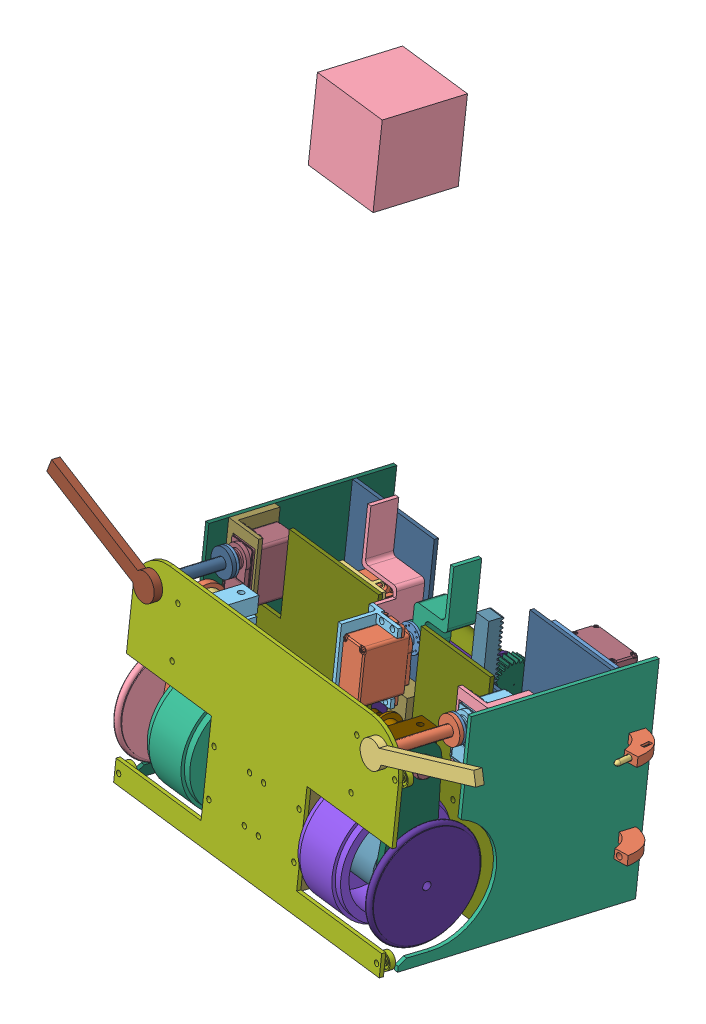
SolidWorks assembly assemblage, configuration Default. Lengths in mm.
Overall size (483.19 497.28 376.15).
92 component instances, 58 part files, 7 mates.
Components (placement in the parent):
- Assem2^assemblage-1: Assem2^assemblage [Default] at origin size (100.3 104.34 84.15)
  - Access_HS-645_BrasRondPetitModele-1: Access_HS-645_BrasRondPetitModele [Défaut] at (-370.7751 -387.697 -20.5572) x (0.014805 -0.999149 0.038511) z (-0.138062 0.036103 0.989765) size (20 5 20)
  - 3-1: 3 [По умолчанию] at (-408.8734 -398.3893 -24.6127) x (0.002879 -0.992343 0.123476) z (-0.138823 0.121884 0.982788) size (53 41.52 20)
  - support statuette-1: support statuette [Default] at (-391.2391 -403.7974 -8.2234) x (-0.002879 0.992343 -0.123476) z (0.138823 -0.121884 -0.982788) size (54 40.5 24)
  - 4-1: 4 [Default] at (-394.7864 -367.7937 -36.5924) x (-0.990313 -0.019971 -0.13741) z (-0.138823 0.121884 0.982788) size (40.67 72.69 34)
  - 3-2: 3 [По умолчанию] at (-353.2671 -390.1635 36.15) x (0.002879 -0.992343 0.123476) z (0.990313 0.019971 0.13741) size (53 41.52 20)
  - 6-1: 6 [Default] at (-364.4184 -365.3949 40.1426) x (0.002879 -0.992343 0.123476) z (0.138823 -0.121884 -0.982788) size (53 30.58 30.75)
  - 2'-1: 2' [Default] at (-347.3265 -385.4811 -7.3447) x (-0.990313 -0.019971 -0.13741) z (0.138823 -0.121884 -0.982788) size (40.4 72.21 20)
  - Access_HS-645_BrasRondPetitModele-2: Access_HS-645_BrasRondPetitModele [Défaut] at (-347.9512 -384.9326 -2.9221) x (0.831423 0.553492 0.048799) z (-0.538018 0.823887 -0.178175) size (20 5 20)
- assemblage v1.1-1: assemblage v1.1 [Default] at (-362.4566 -430.5503 30.4693) x (0.990313 0.019971 0.13741) z (-0.138823 0.121884 0.982788) size (426.3 229.5 291.49)
  - Assem2-1: Assem2 [Default] at (-85.1208 -142.9391 -147.0358) size (284.49 174.6 174.6)
    - BASE-1: BASE [Default] at (61.0944 135.0485 201.8855) size (250 158.15 3)
    - ASSEMB TAMB+SUPPORT-1: ASSEMB TAMB+SUPPORT [Default] at (133.4152 89.0177 175.4805) x (-1 0 0) z (0 0.999702 -0.024415) size (106.04 84.84 84.84)
      - Tombour-1: Tombour [Défaut] at (-5.9119 -3.3103 11.7008) size (103.56 84.84 84.84)
      - small_roue-1: small_roue [Défaut] at (29.0381 -3.3103 11.7008) x (0 0.151035 0.988528) z (-1 0 0) size (23.1 23.1 19.4)
      - support_roulement-1: support_roulement [Défaut] at (9.0881 -3.3103 11.7008) x (0 -0.024415 -0.999702) z (1 0 0) size (45 40 8)
      - accouplement moteur-1: accouplement moteur [Défaut] at (-2.9119 -3.3103 11.7008) x (1 0 0) z (0 -0.034188 0.999415) size (9 25 25)
      - support_roulement-2: support_roulement [Défaut] at (42.4881 -3.3103 11.7008) x (0 -0.024415 -0.999702) z (1 0 0) size (45 40 8)
    - kala-1: kala [Défaut] at (37.3271 135.6343 191.8855) size (90 70 10)
    - assem_enco-7: assem_enco [Default] at (-278.6181 -106.4767 -4.9991) x (0.135936 0.843541 0.519577) z (0.008939 -0.525468 0.850766) size (130.48 81.47 114.09) (flexible)
      - hex screw gradeab fine_iso-1: hex screw gradeab fine_iso [ISO 8676 - M8x1.0 x 16-N] at (389.3011 -418.9502 9.0475) x (-0.135936 0.990677 -0.008939) z (0.955436 0.133476 0.2633) size (21.3 15.01 13)
      - Encodeur TR-1: Encodeur TR [Défaut] at (324.9983 -380.9981 47.0052) x (-0.884066 -0.125369 -0.450234) z (0.135936 -0.990677 0.008939) size (37.8 37.8 52.6)
      - levier-1: levier [Default] at (329.8376 -416.2662 47.3234) x (-0.829282 -0.108844 0.548127) z (0.135936 -0.990677 0.008939) size (114.35 58.34 5)
      - axe-2: axe [Default] at (388.5807 -413.6996 9.0001) x (0.135936 -0.990677 0.008939) z (-0.521438 -0.079215 -0.849604) size (50 24 24)
      - Roue Encodeur-2: Roue Encodeur [Défaut] at (332.9737 -439.1212 47.5296) x (-0.135936 0.990677 -0.008939) z (-0.830604 -0.109044 0.546083) size (16.57 81 81)
      - Part1-2: Part1 [Default] at (363.5392 -389.8747 -1.4264) x (-0.843541 -0.111005 0.525468) z (0.135936 -0.990677 0.008939) size (50 50 15)
    - Mirrorassem_enco-8: Mirrorassem_enco [Default] at (439.2724 -106.4767 -4.9991) x (-0.135936 0.843541 0.519577) z (0.008939 0.525468 -0.850766) size (148.4 84.96 134.9) (flexible)
      - hex screw gradeab fine_iso-1: hex screw gradeab fine_iso [ISO 8676 - M8x1.0 x 16-N] at (389.3011 -418.9502 -9.0475) x (-0.135936 0.990677 0.008939) z (-0.955436 -0.133476 0.2633) size (21.3 15.01 13)
      - MirrorEncodeur TR-1: MirrorEncodeur TR [Défaut] at (324.9983 -380.9981 -47.0052) x (-0.884066 -0.125369 0.450234) z (-0.135936 0.990677 0.008939) size (37.8 37.8 52.6)
      - Mirrorlevier-1: Mirrorlevier [Default] at (329.8376 -416.2662 -47.3234) x (-0.829282 -0.108844 -0.548127) z (-0.135936 0.990677 0.008939) size (114.35 58.34 5)
      - Mirroraxe-1: Mirroraxe [Default] at (388.5807 -413.6996 -9.0001) x (0.135936 -0.990677 -0.008939) z (0.521438 0.079215 -0.849604) size (50 24 24)
      - MirrorRoue Encodeur-1: MirrorRoue Encodeur [Défaut] at (332.9737 -439.1212 -47.5296) x (-0.135936 0.990677 0.008939) z (0.830604 0.109044 0.546083) size (16.57 81 81)
      - MirrorPart1-1: MirrorPart1 [Default] at (363.5392 -389.8747 1.4264) x (-0.843541 -0.111005 -0.525468) z (-0.135936 0.990677 0.008939) size (50 50 15)
    - MirrorASSEMB TAMB+SUPPORT-4: MirrorASSEMB TAMB+SUPPORT [Default] at (27.239 89.0177 175.4805) x (1 0 0) z (0 -0.999702 0.024415) size (88.4 84.84 84.84)
      - MirrorTombour-1: MirrorTombour [Défaut] at (-5.9119 -3.3103 -11.7008) size (40 84.84 84.84)
      - Mirrorsmall_roue-1: Mirrorsmall_roue [Défaut] at (29.0381 -3.3103 -11.7008) x (0 0.151035 -0.988528) z (1 0 0) size (23.1 23.1 19.4)
      - Mirrorsupport_roulement-1: Mirrorsupport_roulement [Défaut] at (9.0881 -3.3103 -11.7008) x (0 -0.024415 0.999702) z (-1 0 0) size (45 40 8)
      - Mirroraccouplement moteur-1: Mirroraccouplement moteur [Défaut] at (-2.9119 -3.3103 -11.7008) x (1 0 0) z (0 0.034188 0.999415) size (9 25 25)
      - Mirrorsupport_roulement-2: Mirrorsupport_roulement [Défaut] at (42.4881 -3.3103 -11.7008) x (0 -0.024415 0.999702) z (-1 0 0) size (45 40 8)
  - assemblage servo-1: assemblage servo [Default] at (-160.2326 88.9637 31.5129) x (0.690395 -0.305055 -0.655969) z (-0.682474 0.02613 -0.730443) size (163.61 67.11 94.82)
    - Access_HS-645_BrasRondPetitModele-1: Access_HS-645_BrasRondPetitModele [Défaut] at (65.5627 21.9831 -12.3813) x (0.698273 0.5203 -0.491633) z (-0.286565 0.832544 0.474079) size (20 5 20)
    - axe support-1: axe support [Default] at (62.6109 22.8388 -15.6683) x (0.748633 0.040573 -0.661742) z (-0.655969 0.190152 -0.730443) size (20 20 53)
    - dezzzez-1: dezzzez [Default] at (23.9087 34.0577 -58.7644) x (0.75207 0.082615 -0.653885) z (0.655969 -0.190152 0.730443) size (108.66 20 6)
    - support el servo-1: support el servo [Default] at (72.965 19.2307 -6.0551) x (0.690395 -0.239966 -0.682474) z (-0.655969 0.190152 -0.730443) size (28.16 56.8 33)
    - Servo-D-2: Servo-D [По умолчанию] at (94.1961 24.0869 15.8447) x (0.305055 0.951976 -0.02613) z (-0.690395 0.239966 0.682474) size (53 41.52 20)
  - r4-12-4-2: r4-12-4 [Default] at (-113.1077 46.2048 55.8497) x (-0.657011 -0.753881 0) z (0.753881 -0.657011 0) size (12 4 12)
  - 7it limin-1: 7it limin [Default] at (-126.7937 5.619 -27.8276) x (0 0 1) z (-1 0 0) size (170.25 158.15 3)
  - assemblage moteur+etage-1: assemblage moteur+etage [Default] at (-103.1195 95.8777 149.8599) x (1 0 0) z (0 0 -1) size (244 158.15 47.87)
    - ETAGE MOUTEUR-1: ETAGE MOUTEUR [Default] at (256.6337 145.964 177.6302) size (244 158.15 3)
    - moteur +roue-1: moteur +roue [Default] at (27.1868 130.6075 195.5653) x (1 0 0) z (0 -1 0) size (86.85 44.87 38.33)
      - moteur+support-1: moteur+support [Default] at (-21.5557 -32.4755 -56.3756) size (79.5 40.9 38.33)
        - supportMoteur-1: supportMoteur [Default] at (46.2429 19.2403 29.8006) size (51 40.7 38)
        - moteurKacem-1: moteurKacem [Default] at (22.5429 39.3442 49.0318) x (-1 0 0) z (0 0.033028 0.999454) size (79.5 37 37)
      - small_roue-1: small_roue [Défaut] at (47.089 13.8648 -7.575) x (0 0.568944 0.822376) z (-1 0 0) size (23.1 23.1 19.4)
    - moteur +roue-2: moteur +roue [Default] at (169.7129 145.7575 195.5653) x (-1 0 0) z (0 1 0) size (86.85 44.87 38.33)
      - moteur+support-1: moteur+support [Default] at (-21.5557 -32.4755 -56.3756) size (79.5 40.9 38.33)
        - supportMoteur-1: supportMoteur [Default] at (46.2429 19.2403 29.8006) size (51 40.7 38)
        - moteurKacem-1: moteurKacem [Default] at (22.5429 39.3442 49.0318) x (-1 0 0) z (0 0.033028 0.999454) size (79.5 37 37)
      - small_roue-1: small_roue [Défaut] at (47.089 13.8648 -7.575) x (0 0.568944 0.822376) z (-1 0 0) size (23.1 23.1 19.4)
  - Mirrorassemblage servo-2: Mirrorassemblage servo [Default] at (150.6452 88.9637 31.5129) x (-0.690395 -0.305055 -0.655969) z (-0.682474 -0.02613 0.730443) size (163.61 67.11 94.82)
    - MirrorAccess_HS-645_BrasRondPetitModele-1: MirrorAccess_HS-645_BrasRondPetitModele [Défaut] at (65.5627 21.9831 12.3813) x (0.698273 0.5203 0.491633) z (0.286565 -0.832544 0.474079) size (20 5 20)
    - Mirroraxe support-1: Mirroraxe support [Default] at (62.6109 22.8388 15.6683) x (0.748633 0.040573 0.661742) z (0.655969 -0.190152 -0.730443) size (20 20 53)
    - Mirrordezzzez-1: Mirrordezzzez [Default] at (23.9087 34.0577 58.7644) x (0.75207 0.082615 0.653885) z (-0.655969 0.190152 0.730443) size (108.66 20 6)
    - Mirrorsupport el servo-1: Mirrorsupport el servo [Default] at (72.965 19.2307 6.0551) x (0.690395 -0.239966 0.682474) z (0.655969 -0.190152 -0.730443) size (28.16 56.8 33)
    - MirrorServo-D-1: MirrorServo-D [По умолчанию] at (94.1961 24.0869 -15.8447) x (0.305055 0.951976 0.02613) z (0.690395 -0.239966 0.682474) size (53 41.52 20)
  - Mirror7it limin-2: Mirror7it limin [Default] at (117.2063 5.619 -27.8276) x (0 0 1) z (-1 0 0) size (170.25 167.82 3)
  - Mirrorr4-12-4-3: Mirrorr4-12-4 [Default] at (103.5203 46.2048 55.8497) x (0.657011 -0.753881 0) z (0.753881 0.657011 0) size (12 4 12)
  - replique-1: replique [Default] at (-4.7937 -88.5236 -90.7703) size (60 60 60)
  - cale replique-1: cale replique [Default] at (-6.1208 -58.5236 -25.7703) x (0 0 -1) z (0 1 0) size (5 30 3)
  - Assem-1: Assem [Default] at (-2.3071 5.8511 16.0473) size (244 158.15 86.12) (flexible)
    - MirrorAccess_HS-645_BrasRondPetitModele-1: MirrorAccess_HS-645_BrasRondPetitModele [Défaut] at (-52.4866 -77.6747 -107.8176) x (-0.658163 0 0.752875) z (0.752875 0 0.658163) size (20 5 20)
    - Servo-D-1: Servo-D [По умолчанию] at (-52.4866 -38.6747 -117.8176) x (0 0 -1) z (-1 0 0) size (53 41.52 20)
    - s9af-1: s9af [Default] at (-2.4866 26.161 -112.8176) size (244 158.15 3)
    - tched replique-1: tched replique [Default] at (-52.4866 -87.1747 -107.8176) x (-0.813575 0 -0.58146) z (0 1 0) size (49.05 41.23 25)
    - support et servo-1: support et servo [Default] at (-73.3835 -34.6287 -140.8176) size (41 29.15 56.5)
  - attach servo-1: attach servo [Default] at (28.2063 -60.4931 -53.0632) x (0 1 0) z (-1 0 0) size (33.78 63 3)
  - Assem6-2: Assem6 [Default] at (-10.3274 -15.7264 -107.2975) x (0 -1 0) z (1 0 0) size (96 86.77 81.2)
    - rack spur rectangular_am-1: rack spur rectangular_am [Metric - Rack-spur - rectangular 1M 20PA 12FW 10PH 100L---SAll] at (-60.2027 -10.5273 12) size (96 51 24)
    - spur gear_am-1: spur gear_am [2] at (-3.4027 14.3327 0) x (0 0 1) z (-0.856307 0.516467 0) size (10 31.88 32)
    - moteur-1: moteur [Default] at (-3.4027 14.3327 -7) x (-0.862944 -0.5053 0) z (0 0 -1) size (24 24 68.2)
    - support moteur-1: support moteur [Default] at (-3.1173 -5.1673 -4) x (0 0 1) z (-1 0 0) size (32.8 32.7 26.4)
  - Mirrorr4-12-4-5: Mirrorr4-12-4 [Default] at (117.8895 -86.0211 50.8497) x (0.657011 -0.753881 0) z (0.753881 0.657011 0) size (12 4 12)
  - Mirrorr4-12-4-6: Mirrorr4-12-4 [Default] at (116.9176 34.3236 50.8497) x (0.171062 -0.98526 0) z (0.98526 0.171062 0) size (12 4 12)
  - Mirrorr4-12-4-7: Mirrorr4-12-4 [Default] at (-126.131 34.2944 50.8497) x (0.015905 -0.999874 0) z (0.999874 0.015905 0) size (12 4 12)
  - Mirrorr4-12-4-8: Mirrorr4-12-4 [Default] at (-124.7919 -85.9696 50.8497) x (0.685449 -0.728121 0) z (0.728121 0.685449 0) size (12 4 12)
  - Assem8-3: Assem8 [Default] at (123.6422 -106.1666 -217.2827) x (0.80126 0.594877 -0.06406) z (-0.112906 0.255477 0.9602) size (95.61 147.83 66.82)
    - Servo-D-1: Servo-D [По умолчанию] at (67.1215 121.1491 150.7487) x (-0.80126 0.587567 0.112906) z (-0.06406 -0.271869 0.9602) size (53 41.52 20)
    - MirrorAccess_HS-645_BrasRondPetitModele_-1: MirrorAccess_HS-645_BrasRondPetitModele_ [Défaut] at (52.2313 85.9312 139.7838) x (0.287559 0.095019 -0.953038) z (-0.75062 0.640405 -0.162634) size (20 5 20)
    - Part7-1: Part7 [Default] at (66.588 102.8456 155.9452) x (-0.80126 0.587567 0.112906) z (-0.06406 -0.271869 0.9602) size (60.3 37.24 23)
    - fouille_bras-2: fouille_bras [Default] at (49.5544 82.5016 138.6342) x (-0.752668 0.639706 -0.15578) z (-0.594877 -0.762137 -0.255477) size (56.89 34.39 72)
    - porte_fil-2: porte_fil [Default] at (77.1126 49.4264 154.9436) x (-0.070641 0.366169 -0.927863) z (-0.684204 0.659091 0.312192) size (28 4 4)
- 1-2: 1 [Default] at (-435.3748 -79.9916 -79.545) x (0.990313 0.019971 0.13741) z (0.002879 -0.992343 0.123476) size (61 61 61)
Mates (geometry in assembly coordinates):
- Distance3: distance = 6 mm: plane of 1-2 through (-409.2287 -136.1979 -37.8469) normal (-0.138823 0.121884 0.982788); plane of assemblage v1.1-1/assemblage moteur+etage-1/ETAGE MOUTEUR-1 through (-206.0136 -480.9378 27.5074) normal (0.138823 -0.121884 -0.982788)
- Parallel1: parallel: plane of assemblage v1.1-1/7it limin-1 through (-493.9044 -472.4602 39.3317) normal (-0.990313 -0.019971 -0.13741); plane of 1-2 through (-461.1696 -144.8511 -106.1789) normal (-0.990313 -0.019971 -0.13741)
- Coincident24: coincident: plane of Assem2^assemblage-1/3-1 through (-371.7654 -387.717 -20.6946) normal (0.990313 0.019971 0.13741); plane of assemblage v1.1-1/assemblage moteur+etage-1/ETAGE MOUTEUR-1 through (-374.0356 -368.897 -7.0691) normal (0.990313 0.019971 0.13741)
- Coincident25: coincident: plane of Assem2^assemblage-1/support statuette-1 through (-391.2391 -403.7974 -8.2234) normal (-0.138823 0.121884 0.982788); plane of assemblage v1.1-1/assemblage moteur+etage-1/ETAGE MOUTEUR-1 through (-206.0136 -480.9378 27.5074) normal (0.138823 -0.121884 -0.982788)
- Coincident26: coincident: plane of Assem2^assemblage-1/support statuette-1 through (-374.1929 -369.6483 -13.1033) normal (-0.002879 0.992343 -0.123476); plane of assemblage v1.1-1/assemblage moteur+etage-1/ETAGE MOUTEUR-1 through (-242.3036 -366.6145 8.203) normal (-0.002879 0.992343 -0.123476)
- Parallel7: parallel: plane of Assem2^assemblage-1/4-1 through (-394.6005 -362.3191 -16.8949) normal (-0.138823 0.121884 0.982788); plane of assemblage v1.1-1/assemblage moteur+etage-1/ETAGE MOUTEUR-1 through (-206.0136 -480.9378 27.5074) normal (0.138823 -0.121884 -0.982788)
- Coincident27: coincident: plane of Assem2^assemblage-1/6-1 through (-366.4598 -363.9133 32.8071) normal (-0.002879 0.992343 -0.123476); plane of assemblage v1.1-1/assemblage moteur+etage-1/ETAGE MOUTEUR-1 through (-242.3036 -366.6145 8.203) normal (-0.002879 0.992343 -0.123476)
